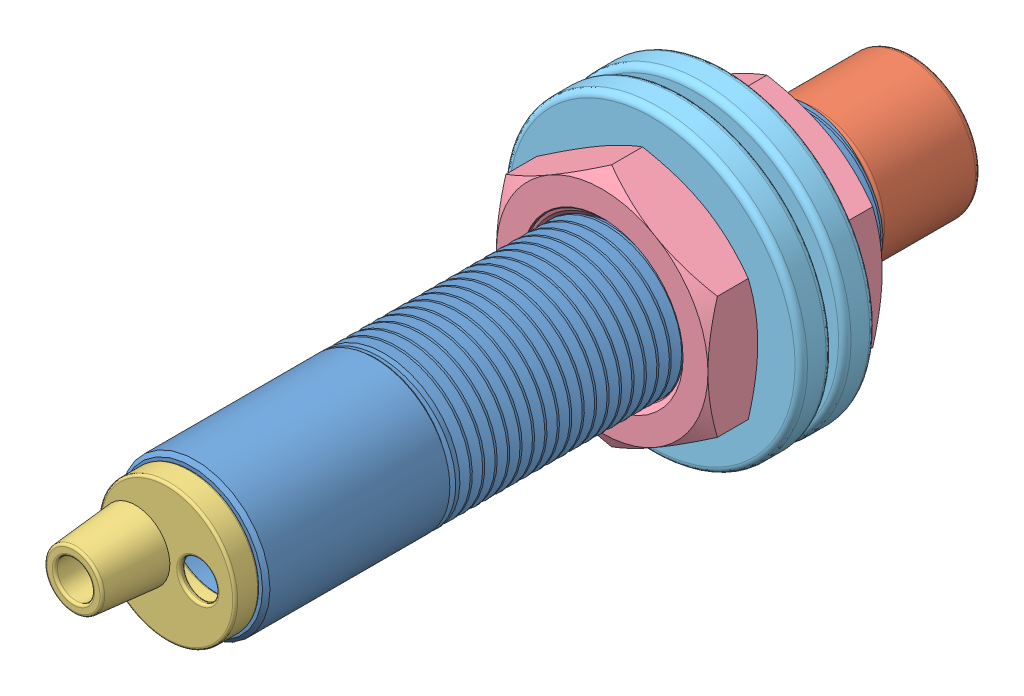
SolidWorks assembly LJ12A3-4-Z-BY, configuration Default. Lengths in mm.
Overall size (24 24 65).
7 component instances, 5 part files, 12 mates.
Components (placement in the parent):
- LJ12A3-4-Z-BY-1-1: LJ12A3-4-Z-BY-1 [Default] at (0.8756 15.1692 -10.7678) size (12.8 13.04 50.55)
- LJ12A3-4-Z-BY-2-2: LJ12A3-4-Z-BY-2 [Default] at (0.8756 15.1692 -18.7678) x (1 0 0) z (0 1 0) size (11 10 11)
- LJ12A3-4-Z-BY-3-1: LJ12A3-4-Z-BY-3 [Default] at (0.8756 15.1692 41.2322) x (1 0 0) z (0 -1 0) size (11 9 11)
- LJ12A3-4-Z-BY-4-1: LJ12A3-4-Z-BY-4 [Default] at (0.8756 15.1692 -7.7678) size (17 19.63 6)
- LJ12A3-4-Z-BY-5-1: LJ12A3-4-Z-BY-5 [Default] at (0.8756 15.1692 -3.7678) size (24 24 2.5)
- LJ12A3-4-Z-BY-5-2: LJ12A3-4-Z-BY-5 [Default] at (0.8756 15.1692 -0.2678) size (24 24 2.5)
- LJ12A3-4-Z-BY-4-2: LJ12A3-4-Z-BY-4 [Default] at (0.8756 15.1692 2.2322) size (17 19.63 6)
Mates (geometry in assembly coordinates):
- Coincident1: coincident anti-aligned: plane of LJ12A3-4-Z-BY-1-1 through (0.8756 15.1692 -10.7678) normal (0 0 -1); plane of LJ12A3-4-Z-BY-2-2 through (0.8756 19.6692 -10.7678) normal (0 0 1)
- Concentric1: concentric aligned: cylinder of LJ12A3-4-Z-BY-1-1 through (0.8756 15.1692 39.2322) axis (0 0 -1) radius 4.5; cylinder of LJ12A3-4-Z-BY-2-2 through (0.8756 15.1692 -18.7678) axis (0 0 -1) radius 4.5
- Concentric2: concentric anti-aligned: cylinder of LJ12A3-4-Z-BY-1-1 through (0.8756 15.1692 39.2322) axis (0 0 -1) radius 4.5; cylinder of LJ12A3-4-Z-BY-3-1 through (0.8756 15.1692 41.2322) axis (0 0 1) radius 4.5
- Coincident2: coincident anti-aligned: plane of LJ12A3-4-Z-BY-1-1 through (0.8756 15.1692 39.2322) normal (0 0 1); plane of LJ12A3-4-Z-BY-3-1 through (0.8756 9.6692 39.2322) normal (0 0 -1)
- Concentric3: concentric aligned: cylinder of LJ12A3-4-Z-BY-1-1 through (0.8756 15.1692 39.2322) axis (0 0 -1) radius 6; circle of LJ12A3-4-Z-BY-4-1
- Distance1: distance = 3 mm aligned: plane of LJ12A3-4-Z-BY-1-1 through (0.8756 15.1692 -10.7678) normal (0 0 -1); plane of LJ12A3-4-Z-BY-4-1 through (0.8756 5.3542 -7.7678) normal (0 0 -1)
- Concentric4: concentric aligned: cylinder of LJ12A3-4-Z-BY-1-1 through (0.8756 15.1692 39.2322) axis (0 0 -1) radius 6; cylinder of LJ12A3-4-Z-BY-5-1 through (0.8756 15.1692 -1.2678) axis (0 0 -1) radius 6.5
- Coincident4: coincident anti-aligned: plane of LJ12A3-4-Z-BY-4-1 through (0.8756 5.3542 -3.7678) normal (0 0 1); plane of LJ12A3-4-Z-BY-5-1 through (0.8756 15.1692 -3.7678) normal (0 0 -1)
- Concentric5: concentric aligned: cylinder of LJ12A3-4-Z-BY-1-1 through (0.8756 15.1692 39.2322) axis (0 0 -1) radius 6; cylinder of LJ12A3-4-Z-BY-5-2 through (0.8756 15.1692 2.2322) axis (0 0 -1) radius 6.5
- Distance2: distance = 1 mm anti-aligned: plane of LJ12A3-4-Z-BY-5-2 through (0.8756 15.1692 -0.2678) normal (0 0 -1); plane of LJ12A3-4-Z-BY-5-1 through (0.8756 15.1692 -1.2678) normal (0 0 1)
- Concentric6: concentric anti-aligned: cylinder of LJ12A3-4-Z-BY-1-1 through (0.8756 15.1692 39.2322) axis (0 0 -1) radius 6; circle of LJ12A3-4-Z-BY-4-2
- Coincident6: coincident anti-aligned: plane of LJ12A3-4-Z-BY-5-2 through (0.8756 15.1692 2.2322) normal (0 0 1); plane of LJ12A3-4-Z-BY-4-2 through (0.8756 5.3542 2.2322) normal (0 0 -1)
